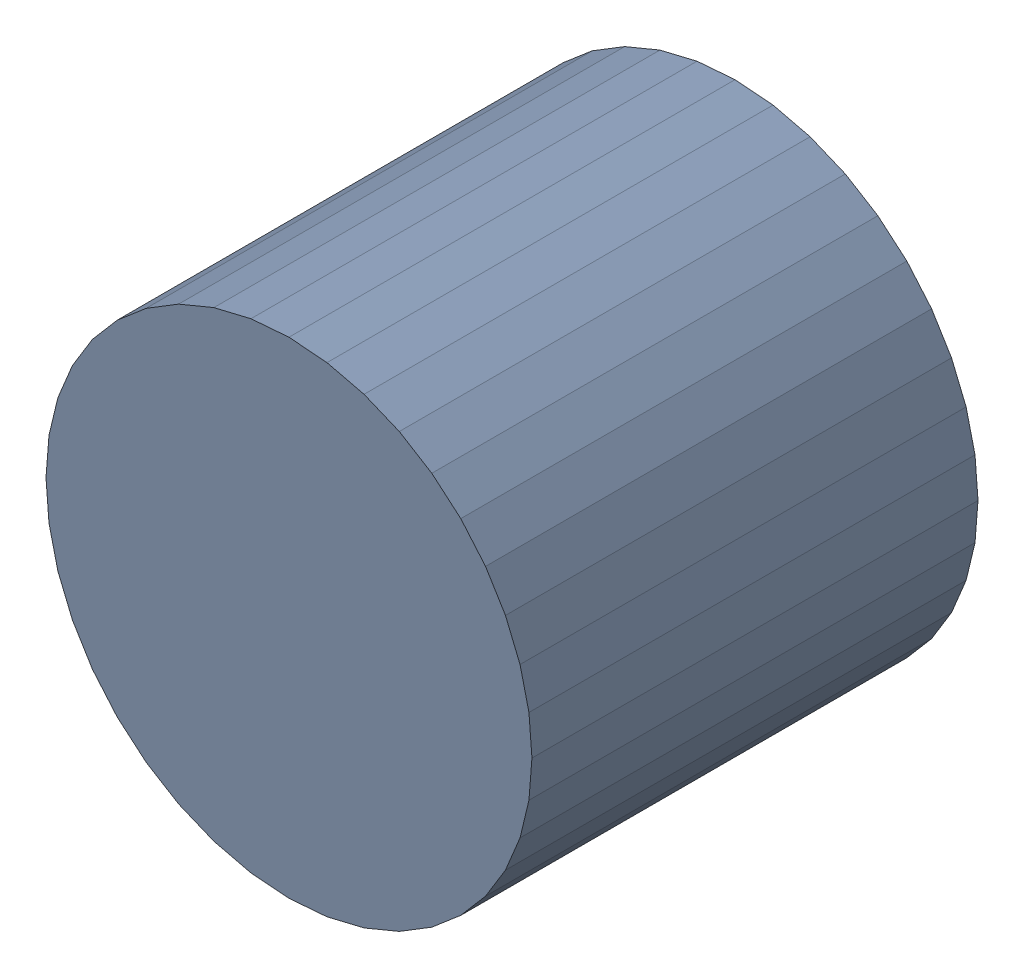
SolidWorks assembly C2, configuration Default. Lengths in mm.
Overall size (6.32 6.32 5.8).
2 component instances, 1 part files, 0 mates.
Components (placement in the parent):
- 384312384-1: 384312384 [Default] at (102.616 74.295 -6.9024) size (6.32 6.32 5.8)
  - Extruded_7-1: Extruded_7 [Default] at origin size (6.32 6.32 5.8)
